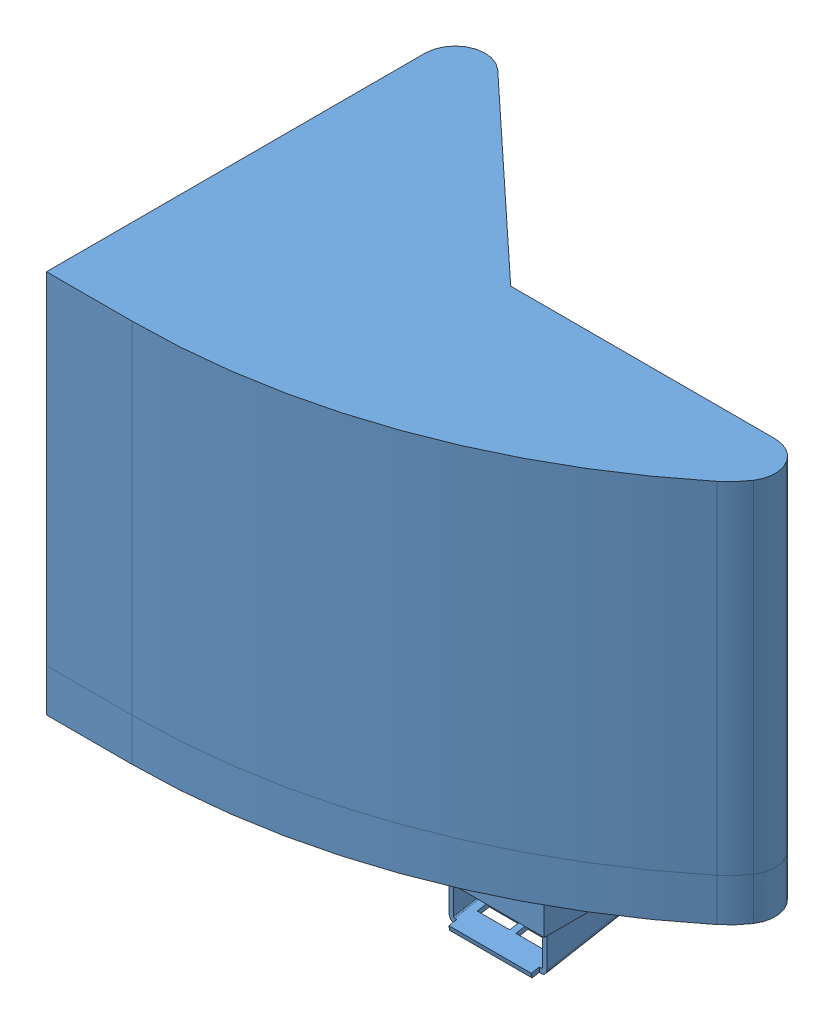
SolidWorks assembly Advisory Panels Ref, configuration Default. Lengths in mm.
Overall size (120.4 105.89 91.26).
4 component instances, 2 part files, 0 mates.
Components (placement in the parent):
- Advisory Panels Ref v5-1: Advisory Panels Ref v5 [Default] at origin size (120.4 105.89 91.26)
- 90283A199-1: 90283A199 [Default] at (123.19 27.94 -6.35) x (1 0 0) z (0 -1 0) (suppressed, hidden)
- 90283A199-2: 90283A199 [Default] at (196.215 27.94 -43.9102) x (1 0 0) z (0 -1 0) (suppressed, hidden)
- 90283A199-3: 90283A199 [Default] at (111.76 27.94 -77.3108) x (1 0 0) z (0 -1 0) (suppressed, hidden)
